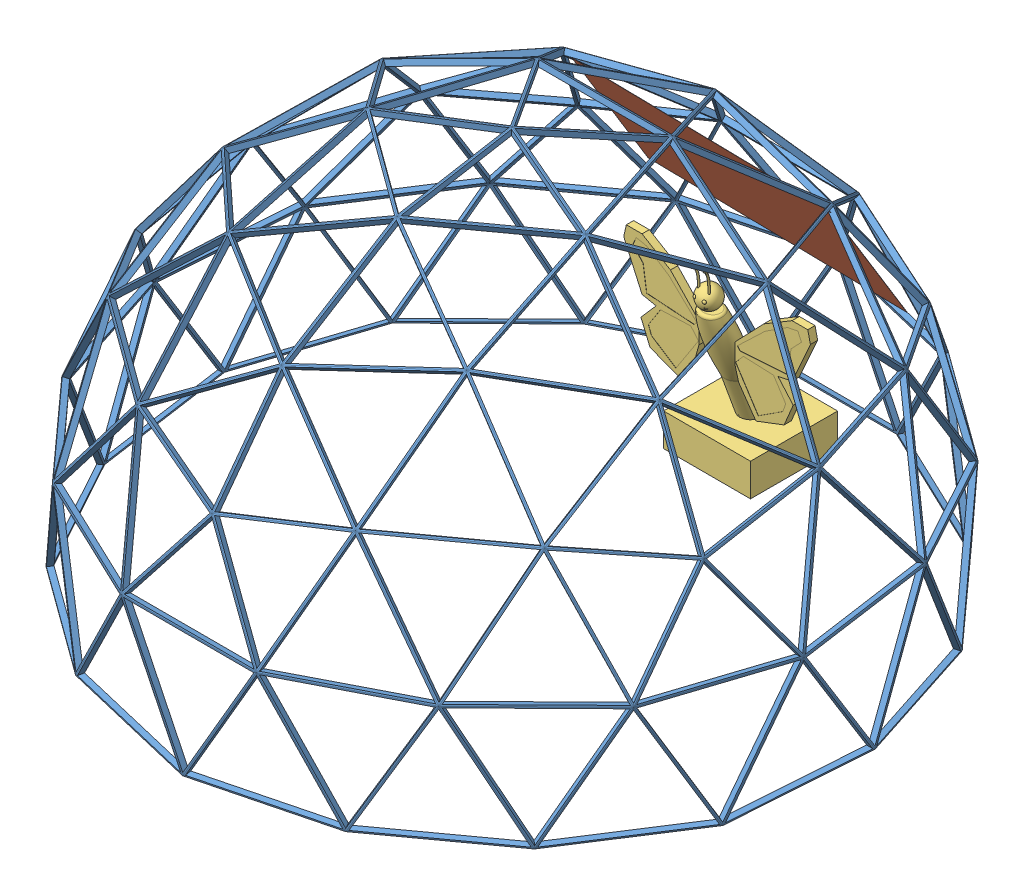
SolidWorks assembly deepflya_test_2, configuration Default. Lengths in mm.
Overall size (9197.62 5570.25 9224).
4 component instances, 4 part files, 7 mates.
Components (placement in the parent):
- 20ft-rad_dome-final-1: 20ft-rad_dome-final [Default] at (4204.108 4140.9106 8690.7246) size (12315.51 7427 12315.51) (hidden)
- 16ft-rad_dome-final-1: 16ft-rad_dome-final [Default] at (4204.108 4140.9106 8690.7246) x (0.999999 0 0.001066) z (-0.001066 0 0.999999) size (9187.81 5570.25 9214.21)
- screen_6_75_X_12-1: screen_6_75_X_12 [Default] at (2470.7109 6651.3927 5052.5055) x (0.999926 -0.009154 0.008059) z (0.003592 0.852517 0.522687) size (3657.6 2.54 2057.4)
- butterfly_base_6_feet-1: butterfly_base_6_feet [Default] at (2630.8737 3097.5192 2290.2163) x (0.999999 0 0.001066) z (-0.001066 0 0.999999) size (2617.43 2571.07 1359.12)
Mates (geometry in assembly coordinates):
- Concentric1: concentric: circle of 20ft-rad_dome-final-1; circle of 16ft-rad_dome-final-1
- Coincident2: coincident: circle of 20ft-rad_dome-final-1; circle of 16ft-rad_dome-final-1
- Coincident15: coincident: circle of 16ft-rad_dome-final-1; plane of ? through (4159.1066 4140.9106 5526.9913) normal (0 -1 0)
- Coincident17: coincident: line of 16ft-rad_dome-final-1 through (6036.6819 8389.7507 6142.4487) axis (-0.978375 0.163862 -0.126223); point of screen_6_75_X_12-1
- Coincident18: coincident: line of 16ft-rad_dome-final-1 through (4174.823 8690.7805 5910.4978) axis (-0.978642 -0.163862 0.124137); point of screen_6_75_X_12-1
- Coincident19: coincident: circle of 16ft-rad_dome-final-1; plane of butterfly_base_6_feet-1 through (4207.6656 4140.9106 5352.8306) normal (0 -1 0)
- Coincident20: coincident: line of 16ft-rad_dome-final-1 through (4204.108 4140.9106 8690.7246) axis (0.001066 0 -0.999999); line of butterfly_base_6_feet-1 through (4207.0159 4140.9106 5962.4302) axis (0.001066 0 -0.999999)
